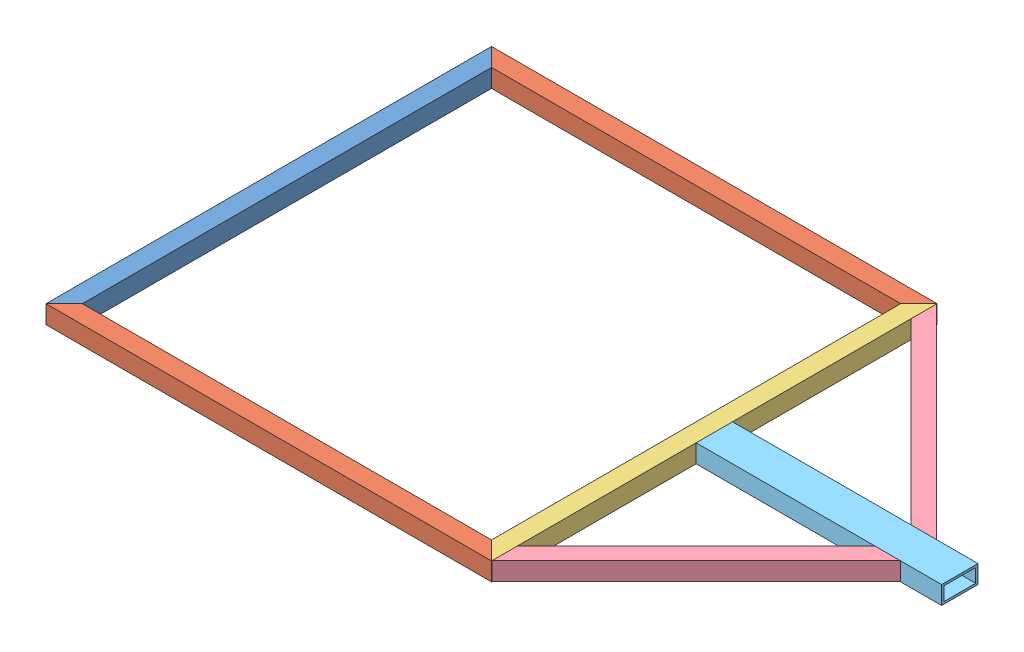
SolidWorks assembly chassis weldment top, configuration Default. Lengths in mm.
Overall size (965.2 25.4 622.3).
7 component instances, 5 part files, 0 mates.
Components (placement in the parent):
- frame member front-1-1: frame member front-1 [Default] at origin size (25.4 25.4 622.3)
- frame member side-1-1: frame member side-1 [Default] at (298.45 0 298.45) x (0 0 1) z (-1 0 0) size (25.4 25.4 622.3)
- frame member side-1-2: frame member side-1 [Default] at (298.45 0 -298.45) x (0 0 -1) z (-1 0 0) size (25.4 25.4 622.3)
- frame member crossbrace middle-1-1: frame member crossbrace middle-1 [Default] at (596.9 0 0) x (-1 0 0) z (0 0 1) size (25.4 25.4 622.3)
- frame member back angle-1-1: frame member back angle-1 [Default] at (743.1813 0 -158.9813) x (-0.707107 0 0.707107) z (-0.707107 0 -0.707107) size (25.4 25.4 403.23)
- frame member back angle-1-2: frame member back angle-1 [Default] at (743.1813 0 158.9813) x (-0.707107 0 -0.707107) z (-0.707107 0 0.707107) size (25.4 25.4 403.23)
- frame member back center-1-1: frame member back center-1 [Default] at (781.05 0 0) x (0 0 -1) z (1 0 0) size (50.8 25.4 342.9)
